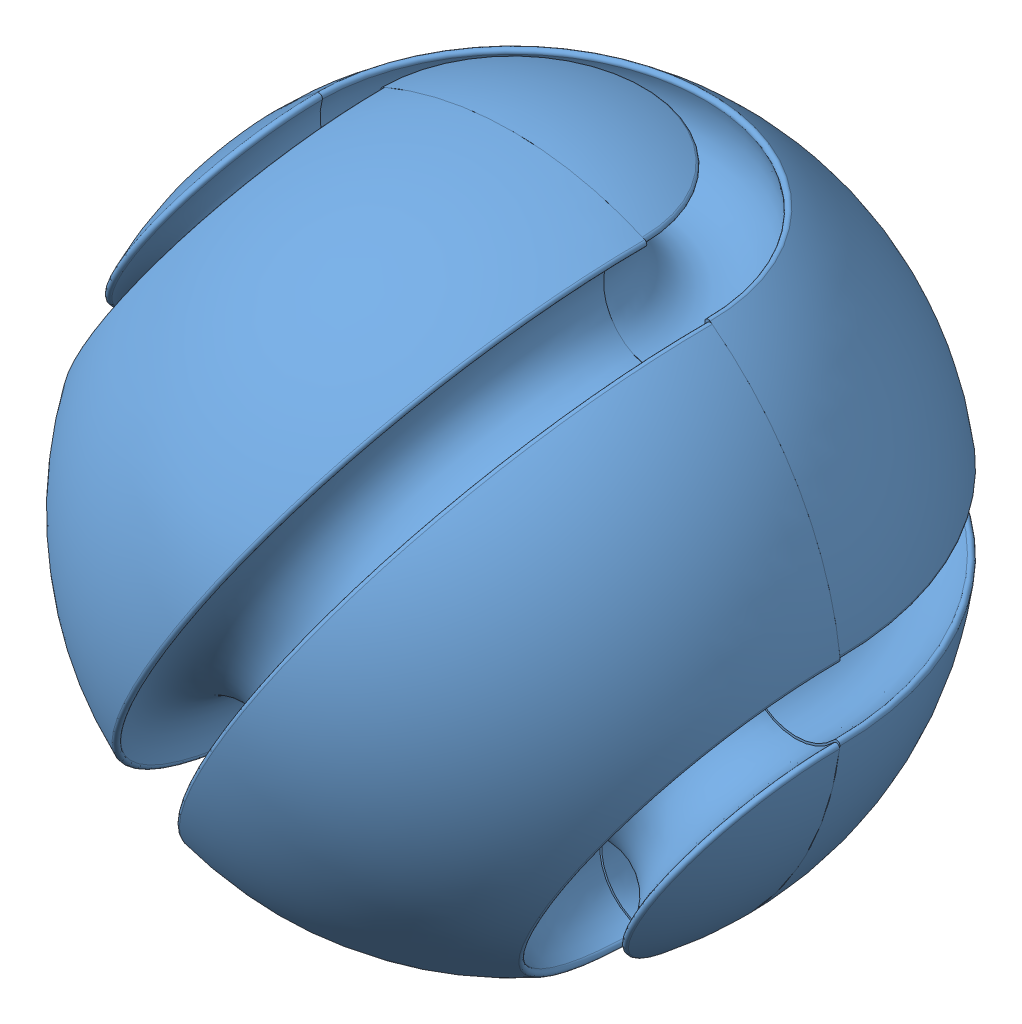
SolidWorks assembly Assem1, configuration Default. Lengths in mm.
Overall size (136.53 136.29 99.3).
3 component instances, 2 part files, 4 mates.
Components (placement in the parent):
- Meia-Peça-1: Meia-Peça [Default] at (49.2884 23.1498 81.0296) size (99.3 100 49.65)
- Part1-1: Part1 [Default] at (49.2884 73.1498 81.0296) x (0 0 -1) z (0.960802 -0.277235 0) size (48.03 30 32.07)
- Meia-Peça-3: Meia-Peça [Default] at (6.186 98.4912 81.0296) x (0.506828 0.862047 0) z (0 0 -1) size (99.3 100 49.65)
Mates (geometry in assembly coordinates):
- Concentric1: concentric aligned: cylinder of Meia-Peça-1 through (49.2884 73.1498 71.0296) axis (0 0 1) radius 10; cylinder of Part1-1 through (49.2884 73.1498 84.1521) axis (0 0 1) radius 10
- Coincident2: coincident anti-aligned: plane of Meia-Peça-1 through (49.2884 73.1498 71.0296) normal (0 0 -1); plane of Part1-1 through (49.2884 73.1498 71.0296) normal (0 0 1)
- Concentric2: concentric anti-aligned: cylinder of Part1-1 through (49.2884 73.1498 84.1521) axis (0 0 1) radius 10; cylinder of Meia-Peça-3 through (49.2884 73.1498 91.0296) axis (0 0 -1) radius 10
- Coincident3: coincident anti-aligned: plane of Part1-1 through (49.2884 73.1498 91.0296) normal (0 0 -1); plane of Meia-Peça-3 through (49.2884 73.1498 91.0296) normal (0 0 1)
